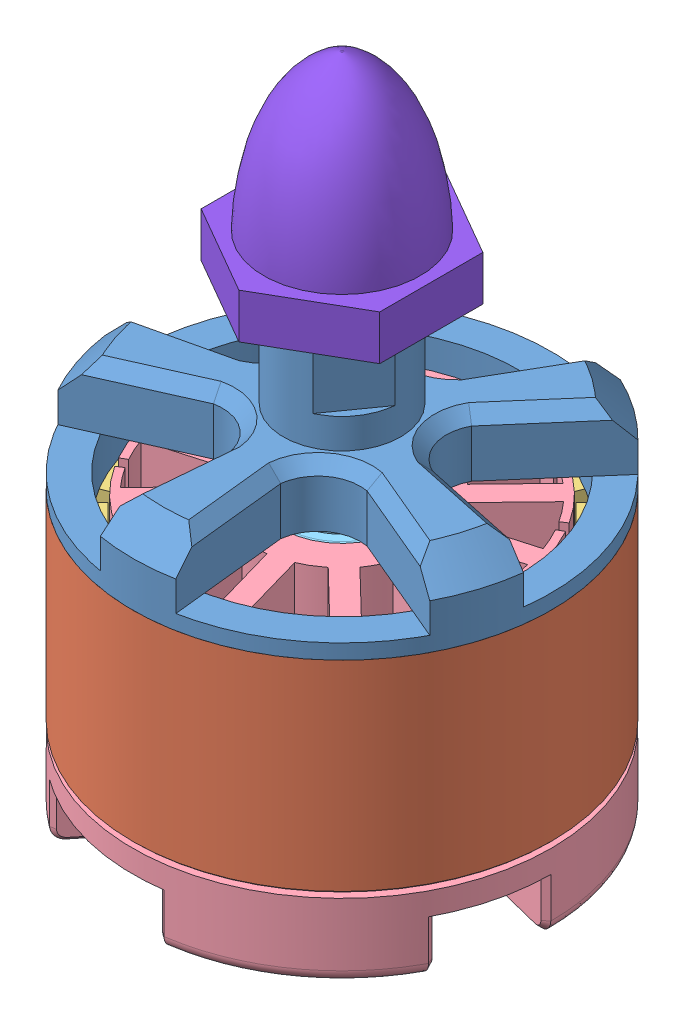
SolidWorks assembly Motor, configuration Default. Lengths in mm.
Overall size (39.42 45.7 39.42).
24 component instances, 8 part files, 17 mates.
Components (placement in the parent):
- Rotor motor-1: Rotor motor [Default] at (-45.3076 1.2115 36.5974) x (0.814589 0 0.580039) z (-0.580039 0 0.814589) size (28 21.43 28)
- CarcasaRotor-1: CarcasaRotor [Default] at (-45.3076 -13.2885 36.5974) x (0.770651 0 -0.637257) z (0.637257 0 0.770651) size (28 13.5 28)
- iman-1: iman [Default] at (-47.0576 -13.2885 25.7158) size (3.5 11.5 1.92)
- iman-2: iman [Default] at (-51.0886 -13.2885 27.2138) x (0.92388 0 -0.382683) z (0.382683 0 0.92388) size (3.5 11.5 1.92)
- iman-3: iman [Default] at (-54.2395 -13.2885 30.1404) x (0.707107 0 -0.707107) z (0.707107 0 0.707107) size (3.5 11.5 1.92)
- iman-4: iman [Default] at (-56.0306 -13.2885 34.05) x (0.382683 0 -0.92388) z (0.92388 0 0.382683) size (3.5 11.5 1.92)
- iman-5: iman [Default] at (-56.1892 -13.2885 38.3474) x (0 0 -1) z (1 0 0) size (3.5 11.5 1.92)
- iman-6: iman [Default] at (-54.6912 -13.2885 42.3785) x (-0.382683 0 -0.92388) z (0.92388 0 -0.382683) size (3.5 11.5 1.92)
- iman-7: iman [Default] at (-51.7646 -13.2885 45.5294) x (-0.707107 0 -0.707107) z (0.707107 0 -0.707107) size (3.5 11.5 1.92)
- iman-8: iman [Default] at (-47.855 -13.2885 47.3205) x (-0.92388 0 -0.382683) z (0.382683 0 -0.92388) size (3.5 11.5 1.92)
- iman-9: iman [Default] at (-43.5576 -13.2885 47.4791) x (-1 0 0) z (0 0 -1) size (3.5 11.5 1.92)
- iman-10: iman [Default] at (-39.5265 -13.2885 45.9811) x (-0.92388 0 0.382683) z (-0.382683 0 -0.92388) size (3.5 11.5 1.92)
- iman-11: iman [Default] at (-36.3756 -13.2885 43.0545) x (-0.707107 0 0.707107) z (-0.707107 0 -0.707107) size (3.5 11.5 1.92)
- iman-12: iman [Default] at (-34.5845 -13.2885 39.1449) x (-0.382683 0 0.92388) z (-0.92388 0 -0.382683) size (3.5 11.5 1.92)
- iman-13: iman [Default] at (-34.4259 -13.2885 34.8474) x (0 0 1) z (-1 0 0) size (3.5 11.5 1.92)
- iman-14: iman [Default] at (-35.9239 -13.2885 30.8164) x (0.382683 0 0.92388) z (-0.92388 0 0.382683) size (3.5 11.5 1.92)
- iman-15: iman [Default] at (-38.8505 -13.2885 27.6655) x (0.707107 0 0.707107) z (-0.707107 0 0.707107) size (3.5 11.5 1.92)
- iman-16: iman [Default] at (-42.7601 -13.2885 25.8744) x (0.92388 0 0.382683) z (-0.382683 0 0.92388) size (3.5 11.5 1.92)
- Base motor-1: Base motor [Default] at (-45.3076 -18.5885 36.5974) x (-0.970038 0 -0.242953) z (-0.242953 0 0.970038) size (28 18.5 28)
- angular contact ball bearing_68_iso-1: angular contact ball bearing_68_iso [ISO 15 ABB - 193 - 8,DE,NC,8_68] at (-45.3076 -17.0885 36.5974) x (0 1 0) z (0 0 1) size (3 8 8)
- angular contact ball bearing_68_iso-2: angular contact ball bearing_68_iso [ISO 15 ABB - 193 - 8,DE,NC,8_68] at (-45.3076 -1.5885 36.5974) x (0 1 0) z (0 0 1) size (3 8 8)
- eje-1: eje [Default] at (-45.3076 4.9115 36.5974) x (0 -1 0) z (0.362973 0 0.9318) size (25 3 3)
- external circlip_bsi-1: external circlip_bsi [BS 3673-4 - S003M] at (-45.3076 -18.5885 36.5974) x (0.998652 0 0.051911) z (0 1 0) size (3.96 5.5 0.4)
- tuerca helice-1: tuerca helice [Default] at (-45.3076 12.2115 36.5974) size (11.95 13.4 13.8)
Mates (geometry in assembly coordinates):
- Concéntrica1: concentric anti-aligned: cylinder of Rotor motor-1 through (-45.3076 -1.7885 36.5974) axis (0 1 0) radius 13; cylinder of CarcasaRotor-1 through (-45.3076 0.2115 36.5974) axis (0 -1 0) radius 13
- Coincidente1: coincident anti-aligned: plane of Rotor motor-1 through (-45.3076 0.2115 36.5974) normal (0 -1 0); plane of CarcasaRotor-1 through (-45.3076 0.2115 36.5974) normal (0 1 0)
- Concéntrica2: concentric aligned: cylinder of CarcasaRotor-1 through (-45.3076 0.2115 36.5974) axis (0 -1 0) radius 13; cylinder of iman-1 through (-45.3076 -1.7885 36.5974) axis (0 -1 0) radius 13
- Coincidente2: coincident anti-aligned: plane of Rotor motor-1 through (-45.3076 -1.7885 36.5974) normal (0 -1 0); plane of iman-1 through (-45.3076 -1.7885 36.5974) normal (0 1 0)
- Coincidente3: coincident aligned: plane of Base motor-1 through (-47.6156 -18.5885 45.8128) normal (0 -1 0); plane of angular contact ball bearing_68_iso-1 through (-48.7826 -18.5885 36.5974) normal (0 -1 0)
- Concéntrica5: concentric anti-aligned: cylinder of Base motor-1 through (-45.3076 -15.5885 36.5974) axis (0 -1 0) radius 4; cylinder of angular contact ball bearing_68_iso-1 through (-45.3076 -37.726 36.5974) axis (0 1 0) radius 4
- Concéntrica6: concentric aligned: cylinder of Rotor motor-1 through (-45.3076 10.2115 36.5974) axis (0 -1 0) radius 1.5; cylinder of Base motor-1 through (-45.3076 -0.0885 36.5974) axis (0 -1 0) radius 1.5
- Coincidente4: coincident aligned: plane of Base motor-1 through (-45.3076 -0.0885 36.5974) normal (0 1 0); plane of angular contact ball bearing_68_iso-2 through (-49.1576 -0.0885 36.5974) normal (0 1 0)
- Concéntrica8: concentric aligned: cylinder of Base motor-1 through (-45.3076 -3.0885 36.5974) axis (0 1 0) radius 4; cylinder of angular contact ball bearing_68_iso-2 through (-45.3076 -22.226 36.5974) axis (0 1 0) radius 4
- Distancia2: distance = 23.8 mm anti-aligned: plane of Rotor motor-1 through (-45.3076 5.2115 36.5974) normal (0 1 0); plane of Base motor-1 through (-47.6156 -18.5885 45.8128) normal (0 -1 0)
- Concéntrica9: concentric aligned: cylinder of angular contact ball bearing_68_iso-1 through (-45.3076 -37.726 36.5974) axis (0 1 0) radius 1.5; cylinder of eje-1 through (-45.3076 4.9115 36.5974) axis (0 1 0) radius 1.5
- Coincidente5: coincident aligned: plane of angular contact ball bearing_68_iso-1 through (-47.5576 -18.5885 36.5974) normal (0 -1 0); plane of eje-1 through (-45.7425 -18.5885 35.4808) normal (0 -1 0)
- Concéntrica10: concentric anti-aligned: cone of eje-1 through (-45.3076 -19.8885 36.5974) axis (0 -1 0); cylinder of external circlip_bsi-1 through (-45.3076 -18.9885 36.5974) axis (0 1 0) radius 1.4
- Coincidente6: coincident anti-aligned: plane of eje-1 through (-45.7425 -18.5885 35.4808) normal (0 -1 0); plane of external circlip_bsi-1 through (-45.3076 -18.5885 36.5974) normal (0 1 0)
- Concéntrica11: concentric aligned: cylinder of eje-1 through (-45.3076 4.9115 36.5974) axis (0 1 0) radius 1.1983; cylinder of external circlip_bsi-1 through (-45.3076 -18.9885 36.5974) axis (0 1 0) radius 1.4
- Concéntrica12: concentric anti-aligned: cylinder of Rotor motor-1 through (-45.3076 20.7523 36.5974) axis (0 1 0) radius 2.25; cylinder of tuerca helice-1 through (-45.3076 22.2115 36.5974) axis (0 -1 0) radius 2.5
- Coincidente7: coincident anti-aligned: plane of Rotor motor-1 through (-45.3076 12.2115 36.5974) normal (0 1 0); plane of tuerca helice-1 through (-45.3076 12.2115 36.5974) normal (0 -1 0)
